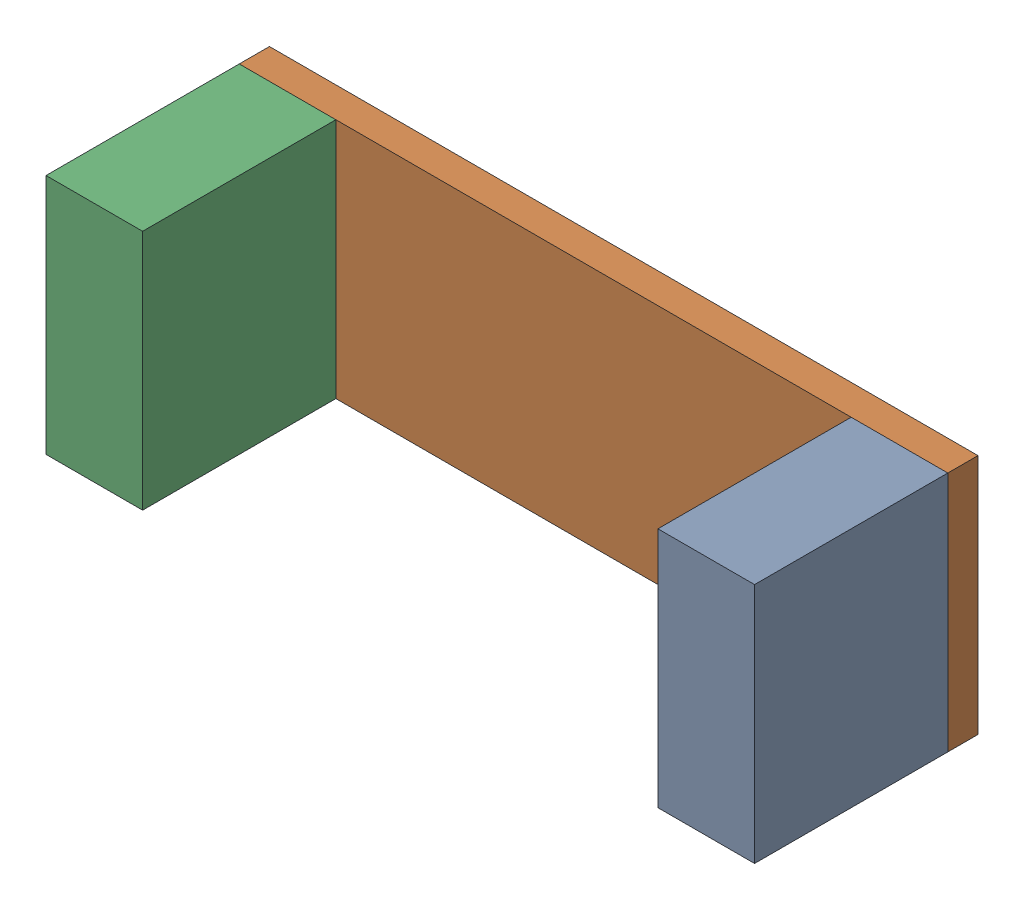
SolidWorks assembly TE-19016-17, configuration Default. Lengths in mm.
Overall size (279.4 95.25 88.11).
3 component instances, 2 part files, 10 mates.
Components (placement in the parent):
- TE-19106-13-2: TE-19106-13 [Default] at (271.7696 47.5704 88.1063) x (1 0 0) z (0 1 0) size (38.1 76.2 95.25)
- TE-19106-14-1: TE-19106-14 [Default] at (134.3246 93.499 0) size (279.4 95.25 11.91)
- TE-19106-13-3: TE-19106-13 [Default] at (30.4696 47.5704 88.1063) x (1 0 0) z (0 1 0) size (38.1 76.2 95.25)
Mates (geometry in assembly coordinates):
- Coincident4: coincident: plane of ?; plane of ? through (134.3246 56.9321 64.0189) normal (0 0 1)
- Coincident5: coincident: unknown of ?; plane of ? through (30.4696 106.2535 64.0189) normal (0 1 0)
- Coincident6: coincident: plane of TE-19106-13-2 through (309.8696 142.8204 88.1063) normal (1 0 0); plane of TE-19106-14-1 through (309.8696 142.8204 11.9062) normal (1 0 0)
- Coincident7: coincident: plane of TE-19106-13-2 through (271.7696 142.8204 11.9062) normal (0 0 -1); plane of TE-19106-14-1 through (134.3246 93.499 11.9062) normal (0 0 1)
- Coincident8: coincident: plane of TE-19106-13-2 through (309.8696 142.8204 88.1063) normal (1 0 0); plane of TE-19106-14-1 through (309.8696 142.8204 11.9062) normal (1 0 0)
- Coincident9: coincident: plane of TE-19106-13-2 through (271.7696 142.8204 88.1063) normal (0 1 0); plane of TE-19106-14-1 through (30.4696 142.8204 11.9062) normal (0 1 0)
- Coincident14: coincident: plane of assembly through (0 0 0) normal (0 0 1); plane of TE-19106-14-1 through (134.3246 93.499 0) normal (0 0 -1); plane of assembly
- Coincident15: coincident: plane of TE-19106-14-1 through (134.3246 93.499 11.9062) normal (0 0 1); plane of ? through (-9.6657 142.8204 11.9062) normal (0 0 -1)
- Coincident16: coincident: plane of TE-19106-14-1 through (30.4696 142.8204 11.9062) normal (0 1 0); plane of ? through (-9.6657 142.8204 88.1063) normal (0 1 0)
- Coincident17: coincident: plane of assembly; plane of assembly; plane of TE-19106-14-1 through (30.4696 142.8204 11.9062) normal (-1 0 0); plane of TE-19106-13-3 through (30.4696 142.8204 88.1063) normal (-1 0 0)
